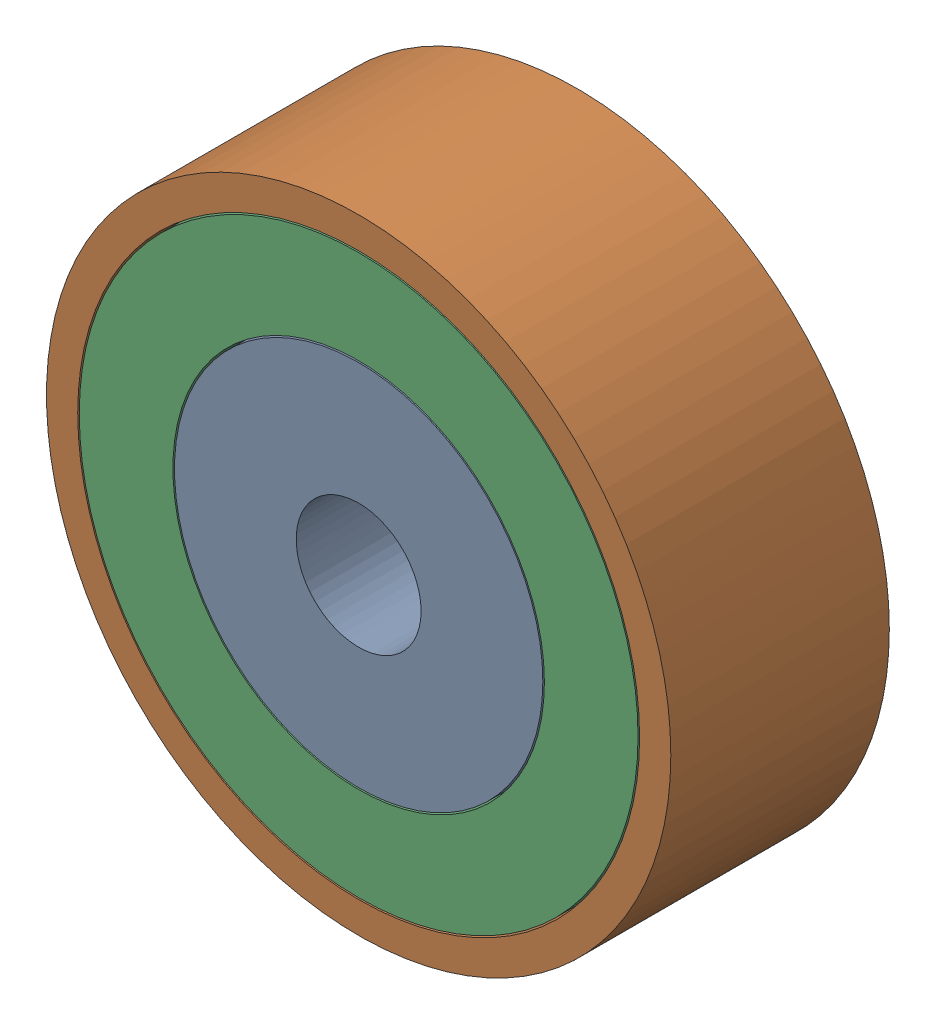
SolidWorks assembly 镜向轴承, configuration 默认. Lengths in mm.
Overall size (20 20 7).
3 component instances, 3 part files, 4 mates.
Components (placement in the parent):
- 镜向轴承内圈-1: 镜向轴承内圈 [默认] at (-5.0655 0.8032 -6.5) size (11.8 11.8 7)
- 镜向轴承外圈-1: 镜向轴承外圈 [默认] at (-5.0655 0.8032 -6.5) size (20 20 7)
- 镜向轴承中圈-1: 镜向轴承中圈 [默认] at (-5.0655 0.8032 -6.5) size (17.9 17.9 7)
Mates (geometry in assembly coordinates):
- 重合1: coincident: plane of ? through (-5.0655 0.8032 -13.5) normal (0 0 -1); plane of ? through (-5.0655 0.8032 -13.5) normal (0 0 -1)
- 重合2: coincident: plane of ? through (-5.0655 0.8032 -13.5) normal (0 0 -1); plane of ? through (-5.0655 0.8032 -13.5) normal (0 0 -1)
- 同心1: concentric: cylinder of ? through (-5.0655 0.8032 -13.5) axis (0 0 1) radius 9; cylinder of ? through (-5.0655 0.8032 -13.5) axis (0 0 1) radius 8.95
- 同心2: concentric: cylinder of ? through (-5.0655 0.8032 -13.5) axis (0 0 1) radius 5.9; cylinder of ? through (-5.0655 0.8032 -13.5) axis (0 0 1) radius 5.95
